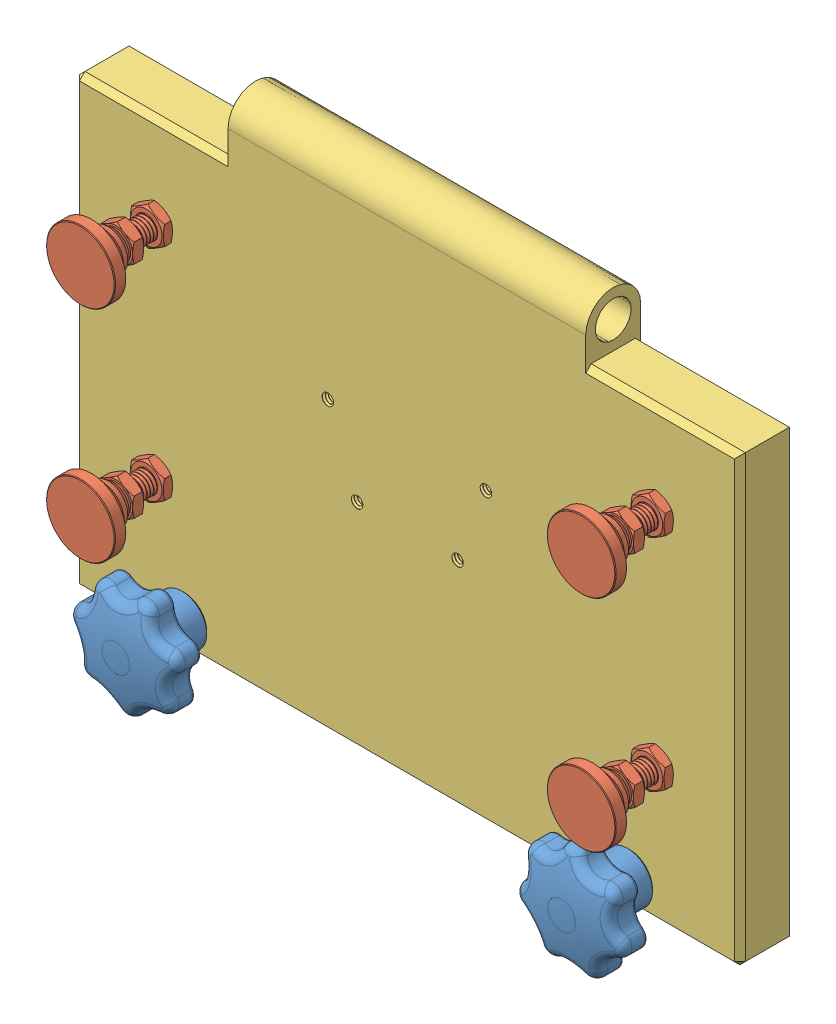
SolidWorks assembly Top Assembly, configuration Default. Lengths in mm.
Overall size (242 196.61 68.25).
7 component instances, 3 part files, 11 mates.
Components (placement in the parent):
- 3855K691_Plastic Knob with Seven Arm Grip-1: 3855K691_Plastic Knob with Seven Arm Grip [3855K691] at (184.0449 41.514 12.5) x (0.927242 -0.374463 0) z (0 0 1)
- 6111K652_Swivel Leveling Mount-1: 6111K652_Swivel Leveling Mount [6111K652] at (174.0449 81.514 23.1667) x (0.99996 0.008929 0) z (-0.008929 0.99996 0)
- Top-1: Top [Default] at (265.0449 122.614 0)
- 3855K691_Plastic Knob with Seven Arm Grip-2: 3855K691_Plastic Knob with Seven Arm Grip [3855K691] at (346.0449 41.514 12.5)
- 6111K652_Swivel Leveling Mount-5: 6111K652_Swivel Leveling Mount [6111K652] at (356.0449 81.514 23.1667) x (0.99996 0.008929 0) z (-0.008929 0.99996 0)
- 6111K652_Swivel Leveling Mount-6: 6111K652_Swivel Leveling Mount [6111K652] at (174.0449 161.514 23.1667) x (0.99996 0.008929 0) z (-0.008929 0.99996 0)
- 6111K652_Swivel Leveling Mount-7: 6111K652_Swivel Leveling Mount [6111K652] at (356.0449 161.514 23.1667) x (0.99996 0.008929 0) z (-0.008929 0.99996 0)
Mates (geometry in assembly coordinates):
- Coincident1: coincident anti-aligned: plane of 6111K652_Swivel Leveling Mount-1 through (173.983 88.4419 20) normal (0 0 -1); plane of Top-1 through (265.0449 122.614 20) normal (0 0 1)
- Coincident2: coincident anti-aligned: plane of Top-1 through (265.0449 122.614 0) normal (0 0 -1)
- Distance3: distance = 50 mm: cylinder of 6111K652_Swivel Leveling Mount-1 through (174.0449 81.514 47.6667) axis (0 0 1) radius 12.5; plane of Top-1 through (144.0449 31.514 20) normal (0 -1 0)
- Distance4: distance = 30 mm: cylinder of 6111K652_Swivel Leveling Mount-1 through (174.0449 81.514 47.6667) axis (0 0 1) radius 12.5; plane of Top-1 through (144.0449 213.714 20) normal (-1 0 0)
- Parallel1: parallel anti-aligned: plane of 3855K691_Plastic Knob with Seven Arm Grip-1 through (184.0449 41.514 20) normal (0 0 -1); plane of Top-1 through (265.0449 122.614 20) normal (0 0 1)
- Coincident4: coincident anti-aligned: plane of 3855K691_Plastic Knob with Seven Arm Grip-1 through (184.0449 41.514 20) normal (0 0 -1); plane of Top-1 through (265.0449 122.614 20) normal (0 0 1)
- Distance5: distance = 40 mm: cylinder of 3855K691_Plastic Knob with Seven Arm Grip-1 through (184.0449 41.514 -20) axis (0 0 -1) radius 9; plane of Top-1 through (144.0449 213.714 20) normal (-1 0 0)
- Distance7: distance = 10 mm: plane of Top-1 through (144.0449 31.514 20) normal (0 -1 0)
- Distance8: distance = 10 mm: plane of Top-1 through (144.0449 31.514 20) normal (0 -1 0); cylinder of 3855K691_Plastic Knob with Seven Arm Grip-2 through (346.0449 41.514 -20) axis (0 0 -1) radius 9
- Coincident6: coincident anti-aligned: plane of Top-1 through (265.0449 122.614 20) normal (0 0 1); plane of 3855K691_Plastic Knob with Seven Arm Grip-2 through (346.0449 41.514 20) normal (0 0 -1)
- Distance9: distance = 40 mm: plane of Top-1 through (386.0449 213.714 20) normal (1 0 0); cylinder of 3855K691_Plastic Knob with Seven Arm Grip-2 through (346.0449 41.514 -20) axis (0 0 -1) radius 9
